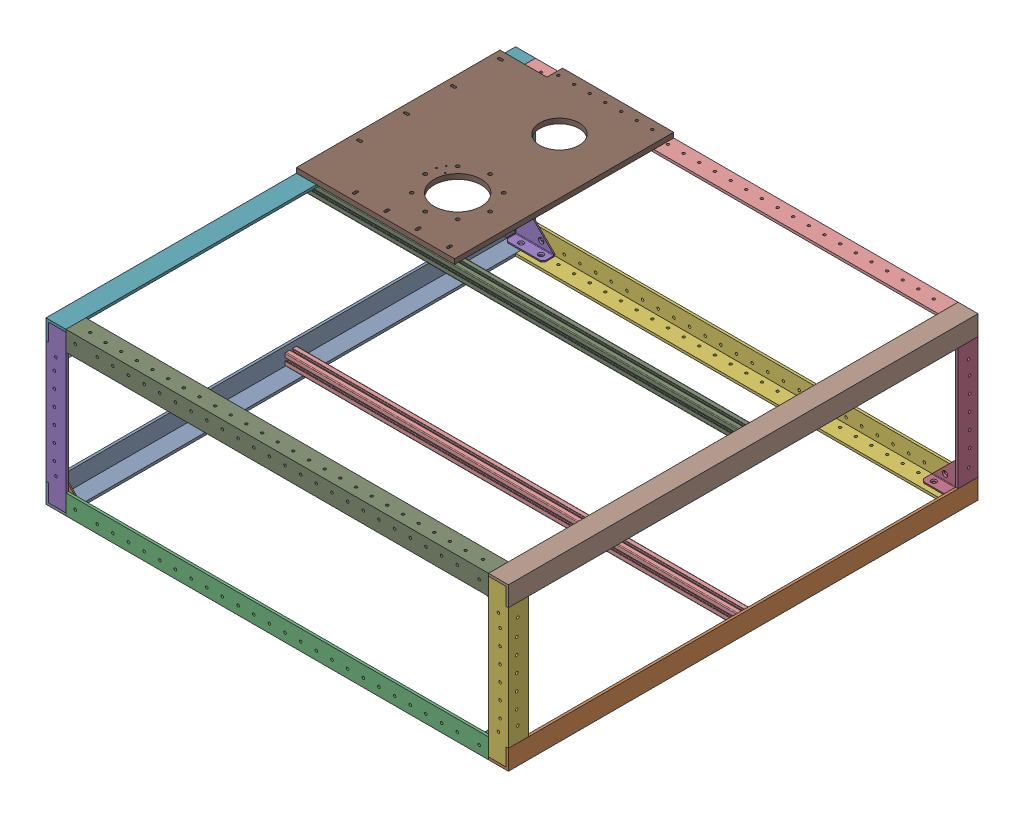
SolidWorks assembly URC Frame Assembly 2025, configuration Default. Lengths in mm.
Overall size (590.8 212.69 600).
23 component instances, 6 part files, 91 mates.
Components (placement in the parent):
- 600mm L Angle 0.125 in-2: 600mm L Angle 0.125 in [8982K421] at (-25.1001 123.5857 -689.9173) size (25.4 25.4 600)
- 600mm L Angle 0.125 in-3: 600mm L Angle 0.125 in [8982K421] at (565.6999 123.5807 1148.4827) x (-1 0 0) z (0 0 -1) size (25.4 25.4 600)
- 200mm L Angle 0.125 in-1: 200mm L Angle 0.125 in [8982K421] at (-25.1001 -892.4443 -70.7173) x (0 0 1) z (0 1 0) size (25.4 25.4 200)
- 200mm L Angle 0.125 in-2: 200mm L Angle 0.125 in [8982K421] at (565.6999 1345.9557 -70.7173) x (0 0 1) z (0 -1 0) size (25.4 25.4 200)
- 200mm L Angle 0.125 in-3: 200mm L Angle 0.125 in [8982K421] at (-25.1001 1345.9607 529.2827) x (0 0 -1) z (0 -1 0) size (25.4 25.4 200)
- 200mm L Angle 0.125 in-4: 200mm L Angle 0.125 in [8982K421] at (565.6999 -892.4443 529.2827) x (0 0 -1) z (0 1 0) size (25.4 25.4 200)
- 600mm L Angle 0.125 in-5: 600mm L Angle 0.125 in [8982K421] at (-25.1001 329.9257 -689.9173) x (0 -1 0) z (0 0 1) size (25.4 25.4 600)
- 600mm L Angle 0.125 in-6: 600mm L Angle 0.125 in [8982K421] at (565.6999 329.9257 -689.9173) x (-1 0 0) z (0 0 1) size (25.4 25.4 600)
- 584 mm L Angle 0.125 in-5: 584 mm L Angle 0.125 in [8982K421] at (-678.9001 329.9257 529.2827) x (0 -1 0) z (1 0 0) size (25.4 25.4 540)
- 584 mm L Angle 0.125 in-6: 584 mm L Angle 0.125 in [8982K421] at (1219.4999 329.9257 -70.7173) x (0 -1 0) z (-1 0 0) size (25.4 25.4 540)
- 1088A31_Inside-Corner Reinforcing Bracket-1: 1088A31_Inside-Corner Reinforcing Bracket [1088A31] at (562.5249 326.7507 524.5837) x (-1 0 0) z (0 -1 0) size (50.93 15.88 50.93)
- 1088A31_Inside-Corner Reinforcing Bracket-2: 1088A31_Inside-Corner Reinforcing Bracket [1088A31] at (-21.9251 326.7507 524.5837) x (0 -1 0) z (1 0 0) size (50.93 15.88 50.93)
- 1088A31_Inside-Corner Reinforcing Bracket-3: 1088A31_Inside-Corner Reinforcing Bracket [1088A31] at (562.5249 126.7557 524.5837) x (0 1 0) z (-1 0 0) size (50.93 15.88 50.93)
- 1088A31_Inside-Corner Reinforcing Bracket-4: 1088A31_Inside-Corner Reinforcing Bracket [1088A31] at (-21.9251 126.7607 524.5837) x (1 0 0) z (0 1 0) size (50.93 15.88 50.93)
- 584 mm L Angle 0.125 in-7: 584 mm L Angle 0.125 in [8982K421] at (1219.4999 123.5807 529.2827) x (0 1 0) z (-1 0 0) size (25.4 25.4 540)
- 1088A31_Inside-Corner Reinforcing Bracket-5: 1088A31_Inside-Corner Reinforcing Bracket [1088A31] at (562.5249 126.7607 -66.0183) x (-1 0 0) z (0 1 0) size (50.93 15.88 50.93)
- 1088A31_Inside-Corner Reinforcing Bracket-6: 1088A31_Inside-Corner Reinforcing Bracket [1088A31] at (-21.9251 126.7607 -66.0183) x (0 1 0) z (1 0 0) size (50.93 15.88 50.93)
- 584 mm L Angle 0.125 in-9: 584 mm L Angle 0.125 in [8982K421] at (-678.9001 123.5857 -70.7173) x (0 1 0) z (1 0 0) size (25.4 25.4 540)
- 1088A31_Inside-Corner Reinforcing Bracket-7: 1088A31_Inside-Corner Reinforcing Bracket [1088A31] at (562.5249 326.7507 -66.0183) x (0 -1 0) z (-1 0 0) size (50.93 15.88 50.93)
- 1088A31_Inside-Corner Reinforcing Bracket-8: 1088A31_Inside-Corner Reinforcing Bracket [1088A31] at (-21.9251 326.7507 -66.0183) x (1 0 0) z (0 -1 0) size (50.93 15.88 50.93)
- T Slot Extrusion-1: T Slot Extrusion [Default] at (92.5749 319.2507 199.2827) x (0 0 1) z (-1 0 0) size (15 15 584.45)
- T Slot Extrusion-2: T Slot Extrusion [Default] at (92.5749 134.2607 219.2827) x (0 0 1) z (-1 0 0) size (15 15 584.45)
- 2025 Arm Plate-1: 2025 Arm Plate [Default] at (105.8999 329.9257 69.2827) size (202 6.35 280)
Mates (geometry in assembly coordinates):
- Coincident10: coincident anti-aligned: plane of 600mm L Angle 0.125 in-2 through (0.2999 123.5857 529.2827) normal (1 0 0); plane of 584 mm L Angle 0.125 in-3 through (0.2999 123.5857 -70.7173) normal (-1 0 0)
- Coincident11: coincident aligned: plane of 600mm L Angle 0.125 in-2 through (0.2999 126.7607 529.2827) normal (0 1 0); plane of 584 mm L Angle 0.125 in-3 through (0.2999 126.7607 -45.3173) normal (0 1 0)
- Coincident12: coincident aligned: plane of 600mm L Angle 0.125 in-2 through (34.8999 148.9857 -70.7173) normal (0 0 -1); plane of 584 mm L Angle 0.125 in-3 through (0.2999 148.9857 -70.7173) normal (0 0 -1)
- Coincident16: coincident aligned: plane of 584 mm L Angle 0.125 in-3 through (0.2999 126.7607 -45.3173) normal (0 1 0); plane of 600mm L Angle 0.125 in-3 through (540.2999 126.7557 -70.7173) normal (0 1 0)
- Coincident17: coincident anti-aligned: plane of 584 mm L Angle 0.125 in-3 through (540.2999 148.9857 -10.7173) normal (1 0 0); plane of 600mm L Angle 0.125 in-3 through (540.2999 123.5807 -70.7173) normal (-1 0 0)
- Coincident18: coincident aligned: plane of 584 mm L Angle 0.125 in-3 through (0.2999 148.9857 -70.7173) normal (0 0 -1); plane of 600mm L Angle 0.125 in-3 through (565.6999 123.5807 -70.7173) normal (0 0 -1)
- Coincident19: coincident anti-aligned: plane of 600mm L Angle 0.125 in-3 through (540.2999 123.5807 -70.7173) normal (-1 0 0); plane of 584 mm L Angle 0.125 in-4 through (540.2999 123.5857 529.2827) normal (1 0 0)
- Coincident20: coincident aligned: plane of 600mm L Angle 0.125 in-3 through (540.2999 126.7557 -70.7173) normal (0 1 0); plane of 584 mm L Angle 0.125 in-4 through (540.2999 126.7607 503.8827) normal (0 1 0)
- Coincident21: coincident aligned: plane of 600mm L Angle 0.125 in-2 through (-25.1001 123.5857 529.2827) normal (0 0 1); plane of 584 mm L Angle 0.125 in-4 through (540.2999 148.9857 529.2827) normal (0 0 1)
- Coincident22: coincident aligned: plane of 600mm L Angle 0.125 in-2 through (-25.1001 148.9857 529.2827) normal (-1 0 0); plane of 200mm L Angle 0.125 in-1 through (-25.1001 326.7557 -70.7173) normal (-1 0 0)
- Coincident23: coincident aligned: plane of 584 mm L Angle 0.125 in-3 through (0.2999 148.9857 -70.7173) normal (0 0 -1); plane of 200mm L Angle 0.125 in-1 through (0.2999 326.7557 -70.7173) normal (0 0 -1)
- Coincident24: coincident anti-aligned: plane of 600mm L Angle 0.125 in-2 through (-21.9251 148.9857 529.2827) normal (0 1 0); plane of 200mm L Angle 0.125 in-1 through (11.8289 148.9857 -45.3173) normal (0 -1 0)
- Coincident25: coincident anti-aligned: plane of 600mm L Angle 0.125 in-3 through (540.2999 126.7557 -70.7173) normal (0 1 0); plane of 200mm L Angle 0.125 in-2 through (565.6999 126.7557 -70.7173) normal (0 -1 0)
- Coincident26: coincident aligned: plane of 584 mm L Angle 0.125 in-3 through (0.2999 148.9857 -70.7173) normal (0 0 -1); plane of 200mm L Angle 0.125 in-2 through (540.2999 126.7557 -70.7173) normal (0 0 -1)
- Coincident27: coincident aligned: plane of 600mm L Angle 0.125 in-3 through (565.6999 148.9807 -70.7173) normal (1 0 0); plane of 200mm L Angle 0.125 in-2 through (565.6999 126.7557 -70.7173) normal (1 0 0)
- Coincident28: coincident anti-aligned: plane of 600mm L Angle 0.125 in-2 through (0.2999 126.7607 529.2827) normal (0 1 0); plane of 200mm L Angle 0.125 in-3 through (-25.1001 126.7607 529.2827) normal (0 -1 0)
- Coincident29: coincident aligned: plane of 584 mm L Angle 0.125 in-4 through (540.2999 148.9857 529.2827) normal (0 0 1); plane of 200mm L Angle 0.125 in-3 through (0.2999 126.7607 529.2827) normal (0 0 1)
- Coincident30: coincident aligned: plane of 600mm L Angle 0.125 in-2 through (-25.1001 148.9857 529.2827) normal (-1 0 0); plane of 200mm L Angle 0.125 in-3 through (-25.1001 126.7607 529.2827) normal (-1 0 0)
- Coincident33: coincident anti-aligned: plane of 600mm L Angle 0.125 in-3 through (540.2999 126.7557 -70.7173) normal (0 1 0); plane of 200mm L Angle 0.125 in-4 through (540.2999 126.7557 469.2827) normal (0 -1 0)
- Coincident34: coincident aligned: plane of 584 mm L Angle 0.125 in-4 through (540.2999 148.9857 529.2827) normal (0 0 1); plane of 200mm L Angle 0.125 in-4 through (540.2999 326.7557 529.2827) normal (0 0 1)
- Coincident35: coincident aligned: plane of 600mm L Angle 0.125 in-3 through (565.6999 148.9807 -70.7173) normal (1 0 0); plane of 200mm L Angle 0.125 in-4 through (565.6999 326.7557 529.2827) normal (1 0 0)
- Coincident36: coincident aligned: plane of 200mm L Angle 0.125 in-3 through (-25.1001 126.7607 529.2827) normal (-1 0 0); plane of 600mm L Angle 0.125 in-4 through (-25.1001 129.9357 250.1294) normal (-1 0 0)
- Coincident37: coincident anti-aligned: plane of 600mm L Angle 0.125 in-2 through (0.2999 126.7607 529.2827) normal (0 1 0); plane of 600mm L Angle 0.125 in-4 through (-21.9251 126.7607 250.1294) normal (0 -1 0)
- Coincident39: coincident anti-aligned: plane of 200mm L Angle 0.125 in-1 through (11.8289 304.5257 -45.3173) normal (0 1 0); plane of 600mm L Angle 0.125 in-5 through (-25.1001 304.5257 529.2827) normal (0 -1 0)
- Coincident40: coincident aligned: plane of 200mm L Angle 0.125 in-1 through (0.2999 326.7557 -70.7173) normal (0 0 -1); plane of 600mm L Angle 0.125 in-5 through (0.2999 269.9257 -70.7173) normal (0 0 -1)
- Coincident41: coincident aligned: plane of 200mm L Angle 0.125 in-1 through (-25.1001 326.7557 -70.7173) normal (-1 0 0); plane of 600mm L Angle 0.125 in-5 through (-25.1001 329.9257 529.2827) normal (-1 0 0)
- Coincident42: coincident aligned: plane of 200mm L Angle 0.125 in-4 through (565.6999 326.7557 529.2827) normal (1 0 0); plane of 600mm L Angle 0.125 in-6 through (565.6999 304.5257 529.2827) normal (1 0 0)
- Coincident43: coincident anti-aligned: plane of 200mm L Angle 0.125 in-4 through (528.7709 304.5257 503.8827) normal (0 1 0); plane of 600mm L Angle 0.125 in-6 through (562.5249 304.5257 529.2827) normal (0 -1 0)
- Coincident44: coincident aligned: plane of 200mm L Angle 0.125 in-4 through (540.2999 326.7557 529.2827) normal (0 0 1); plane of 600mm L Angle 0.125 in-6 through (565.6999 329.9257 529.2827) normal (0 0 1)
- Coincident45: coincident anti-aligned: plane of 600mm L Angle 0.125 in-6 through (540.2999 329.9257 529.2827) normal (-1 0 0); plane of 584 mm L Angle 0.125 in-5 through (540.2999 329.9257 529.2827) normal (1 0 0)
- Coincident46: coincident aligned: plane of 200mm L Angle 0.125 in-4 through (540.2999 326.7557 529.2827) normal (0 0 1); plane of 584 mm L Angle 0.125 in-5 through (540.2999 329.9257 529.2827) normal (0 0 1)
- Coincident47: coincident aligned: plane of 600mm L Angle 0.125 in-6 through (565.6999 329.9257 529.2827) normal (0 1 0); plane of 584 mm L Angle 0.125 in-5 through (540.2999 329.9257 503.8827) normal (0 1 0)
- Coincident48: coincident aligned: plane of 200mm L Angle 0.125 in-2 through (540.2999 126.7557 -70.7173) normal (0 0 -1); plane of 584 mm L Angle 0.125 in-6 through (0.2999 329.9257 -70.7173) normal (0 0 -1)
- Coincident49: coincident aligned: plane of 600mm L Angle 0.125 in-6 through (565.6999 329.9257 529.2827) normal (0 1 0); plane of 584 mm L Angle 0.125 in-6 through (0.2999 329.9257 -45.3173) normal (0 1 0)
- Coincident50: coincident anti-aligned: plane of 600mm L Angle 0.125 in-5 through (0.2999 326.7507 529.2827) normal (1 0 0); plane of 584 mm L Angle 0.125 in-6 through (0.2999 329.9257 -70.7173) normal (-1 0 0)
- Concentric1: concentric aligned: circle of 600mm L Angle 0.125 in-6; circle of 1088A31_Inside-Corner Reinforcing Bracket-1
- Parallel2: parallel aligned: plane of 200mm L Angle 0.125 in-4 through (565.6999 326.7557 503.8827) normal (0 0 -1); plane of 1088A31_Inside-Corner Reinforcing Bracket-1 through (562.5249 325.2267 510.2327) normal (0 0 -1)
- Coincident52: coincident anti-aligned: plane of 200mm L Angle 0.125 in-4 through (562.5249 326.7557 503.8827) normal (-1 0 0); plane of 1088A31_Inside-Corner Reinforcing Bracket-1 through (562.5249 275.9507 524.5837) normal (1 0 0)
- Concentric2: concentric anti-aligned: circle of 600mm L Angle 0.125 in-5; circle of 1088A31_Inside-Corner Reinforcing Bracket-2
- Coincident53: coincident anti-aligned: plane of 200mm L Angle 0.125 in-3 through (-21.9251 126.7607 526.1077) normal (0 0 -1); plane of 1088A31_Inside-Corner Reinforcing Bracket-2 through (-20.4011 325.2267 526.1077) normal (0 0 1)
- Coincident54: coincident anti-aligned: plane of 600mm L Angle 0.125 in-5 through (-21.9251 304.5257 529.2827) normal (1 0 0); plane of 1088A31_Inside-Corner Reinforcing Bracket-2 through (-21.9251 275.9507 510.2327) normal (-1 0 0)
- Coincident55: coincident anti-aligned: plane of 200mm L Angle 0.125 in-4 through (562.5249 326.7557 503.8827) normal (-1 0 0); plane of 1088A31_Inside-Corner Reinforcing Bracket-3 through (562.5249 177.5557 510.2327) normal (1 0 0)
- Coincident56: coincident anti-aligned: plane of 200mm L Angle 0.125 in-4 through (562.5249 326.7557 526.1077) normal (0 0 -1); plane of 1088A31_Inside-Corner Reinforcing Bracket-3 through (561.0009 128.2797 526.1077) normal (0 0 1)
- Coincident57: coincident anti-aligned: plane of 600mm L Angle 0.125 in-3 through (540.2999 126.7557 -70.7173) normal (0 1 0); plane of 1088A31_Inside-Corner Reinforcing Bracket-3 through (511.7249 126.7557 524.5837) normal (0 -1 0)
- Coincident58: coincident anti-aligned: plane of 600mm L Angle 0.125 in-2 through (0.2999 126.7607 529.2827) normal (0 1 0); plane of 1088A31_Inside-Corner Reinforcing Bracket-4 through (28.8749 126.7607 510.2327) normal (0 -1 0)
- Coincident59: coincident anti-aligned: plane of 200mm L Angle 0.125 in-3 through (-21.9251 126.7607 526.1077) normal (0 0 -1); plane of 1088A31_Inside-Corner Reinforcing Bracket-4 through (-20.4011 128.2847 526.1077) normal (0 0 1)
- Coincident60: coincident anti-aligned: plane of 200mm L Angle 0.125 in-3 through (-21.9251 126.7607 503.8827) normal (1 0 0); plane of 1088A31_Inside-Corner Reinforcing Bracket-4 through (-21.9251 177.5607 524.5837) normal (-1 0 0)
- Coincident61: coincident aligned: plane of 600mm L Angle 0.125 in-3 through (565.6999 123.5807 -70.7173) normal (0 -1 0); plane of 584 mm L Angle 0.125 in-7 through (0.2999 123.5807 503.8827) normal (0 -1 0)
- Coincident62: coincident aligned: plane of 200mm L Angle 0.125 in-4 through (540.2999 326.7557 529.2827) normal (0 0 1); plane of 584 mm L Angle 0.125 in-7 through (0.2999 123.5807 529.2827) normal (0 0 1)
- Coincident64: coincident anti-aligned: plane of 600mm L Angle 0.125 in-3 through (540.2999 123.5807 -70.7173) normal (-1 0 0); plane of 584 mm L Angle 0.125 in-7 through (540.2999 183.5807 503.8827) normal (1 0 0)
- Coincident65: coincident aligned: plane of 200mm L Angle 0.125 in-2 through (540.2999 126.7557 -70.7173) normal (0 0 -1); plane of 600mm L Angle 0.125 in-6 through (505.6999 304.5257 -70.7173) normal (0 0 -1)
- Coincident66: coincident: plane of 584 mm L Angle 0.125 in-3 through (0.2999 126.7607 -45.3173) normal (0 1 0); plane of 1088A31_Inside-Corner Reinforcing Bracket-5 through (511.7249 126.7607 -51.6673) normal (0 -1 0)
- Coincident67: coincident: plane of 584 mm L Angle 0.125 in-3 through (0.2999 126.7607 -67.5423) normal (0 0 1); plane of 1088A31_Inside-Corner Reinforcing Bracket-5 through (561.0009 128.2847 -67.5423) normal (0 0 -1)
- Coincident68: coincident anti-aligned: plane of 200mm L Angle 0.125 in-2 through (562.5249 126.7557 -45.3173) normal (-1 0 0); plane of 1088A31_Inside-Corner Reinforcing Bracket-5 through (562.5249 177.5607 -66.0183) normal (1 0 0)
- Parallel3: parallel anti-aligned: plane of 584 mm L Angle 0.125 in-7 through (0.2999 126.7557 503.8827) normal (0 0 -1); plane of 584 mm L Angle 0.125 in-8 through (0.2999 123.5857 -45.3173) normal (0 0 1)
- Coincident70: coincident aligned: plane of 600mm L Angle 0.125 in-2 through (-25.1001 123.5857 529.2827) normal (0 -1 0); plane of 584 mm L Angle 0.125 in-8 through (0.2999 123.5857 -70.7173) normal (0 -1 0)
- Coincident71: coincident aligned: plane of 200mm L Angle 0.125 in-1 through (0.2999 326.7557 -70.7173) normal (0 0 -1); plane of 584 mm L Angle 0.125 in-8 through (0.2999 148.9857 -70.7173) normal (0 0 -1)
- Coincident72: coincident anti-aligned: plane of 200mm L Angle 0.125 in-1 through (0.2999 326.7557 -67.5423) normal (1 0 0); plane of 584 mm L Angle 0.125 in-8 through (0.2999 123.5857 -70.7173) normal (-1 0 0)
- Coincident73: coincident anti-aligned: plane of 1088A31_Inside-Corner Reinforcing Bracket-5 through (561.0009 128.2847 -67.5423) normal (0 0 -1); plane of 584 mm L Angle 0.125 in-8 through (0.2999 126.7607 -67.5423) normal (0 0 1)
- Coincident74: coincident aligned: plane of 200mm L Angle 0.125 in-2 through (540.2999 126.7557 -70.7173) normal (0 0 -1); plane of 584 mm L Angle 0.125 in-8 through (0.2999 148.9857 -70.7173) normal (0 0 -1)
- Coincident75: coincident aligned: plane of 600mm L Angle 0.125 in-3 through (565.6999 123.5807 -70.7173) normal (0 0 -1); plane of 584 mm L Angle 0.125 in-8 through (0.2999 148.9857 -70.7173) normal (0 0 -1)
- Coincident76: coincident aligned: plane of 600mm L Angle 0.125 in-2 through (34.8999 148.9857 -70.7173) normal (0 0 -1); plane of 584 mm L Angle 0.125 in-8 through (0.2999 148.9857 -70.7173) normal (0 0 -1)
- Coincident77: coincident aligned: plane of 600mm L Angle 0.125 in-5 through (0.2999 329.9257 529.2827) normal (0 1 0); plane of 584 mm L Angle 0.125 in-6 through (0.2999 329.9257 -45.3173) normal (0 1 0)
- Coincident78: coincident anti-aligned: plane of 600mm L Angle 0.125 in-5 through (0.2999 326.7507 529.2827) normal (1 0 0); plane of 584 mm L Angle 0.125 in-5 through (0.2999 269.9257 503.8827) normal (-1 0 0)
- Coincident79: coincident anti-aligned: plane of 200mm L Angle 0.125 in-1 through (-21.9251 326.7557 -67.5423) normal (0 0 1); plane of 1088A31_Inside-Corner Reinforcing Bracket-6 through (-20.4011 128.2847 -67.5423) normal (0 0 -1)
- Coincident80: coincident anti-aligned: plane of 200mm L Angle 0.125 in-1 through (-21.9251 326.7557 -45.3173) normal (1 0 0); plane of 1088A31_Inside-Corner Reinforcing Bracket-6 through (-21.9251 177.5607 -51.6673) normal (-1 0 0)
- Coincident81: coincident anti-aligned: plane of 584 mm L Angle 0.125 in-8 through (0.2999 126.7607 -45.3173) normal (0 1 0); plane of 1088A31_Inside-Corner Reinforcing Bracket-6 through (28.8749 126.7607 -66.0183) normal (0 -1 0)
- Coincident82: coincident aligned: plane of 600mm L Angle 0.125 in-2 through (0.2999 126.7607 529.2827) normal (0 1 0); plane of 584 mm L Angle 0.125 in-9 through (540.2999 126.7607 -67.5423) normal (0 1 0)
- Coincident83: coincident anti-aligned: plane of 1088A31_Inside-Corner Reinforcing Bracket-6 through (-20.4011 128.2847 -67.5423) normal (0 0 -1); plane of 584 mm L Angle 0.125 in-9 through (540.2999 148.9857 -67.5423) normal (0 0 1)
- Coincident84: coincident anti-aligned: plane of 600mm L Angle 0.125 in-3 through (540.2999 123.5807 -70.7173) normal (-1 0 0); plane of 584 mm L Angle 0.125 in-9 through (540.2999 123.5857 -70.7173) normal (1 0 0)
- Coincident85: coincident anti-aligned: plane of 1088A31_Inside-Corner Reinforcing Bracket-5 through (511.7249 126.7607 -51.6673) normal (0 -1 0); plane of 584 mm L Angle 0.125 in-9 through (540.2999 126.7607 -67.5423) normal (0 1 0)
- Coincident86: coincident anti-aligned: plane of 1088A31_Inside-Corner Reinforcing Bracket-5 through (561.0009 128.2847 -67.5423) normal (0 0 -1); plane of 584 mm L Angle 0.125 in-9 through (540.2999 148.9857 -67.5423) normal (0 0 1)
- Coincident87: coincident anti-aligned: plane of 200mm L Angle 0.125 in-2 through (562.5249 126.7557 -67.5423) normal (0 0 1); plane of 1088A31_Inside-Corner Reinforcing Bracket-5 through (561.0009 128.2847 -67.5423) normal (0 0 -1)
- Coincident88: coincident aligned: plane of 600mm L Angle 0.125 in-3 through (565.6999 123.5807 -70.7173) normal (0 0 -1); plane of 200mm L Angle 0.125 in-2 through (540.2999 126.7557 -70.7173) normal (0 0 -1)
- Coincident89: coincident aligned: plane of 600mm L Angle 0.125 in-2 through (-25.1001 123.5857 529.2827) normal (0 0 1); plane of 200mm L Angle 0.125 in-3 through (0.2999 126.7607 529.2827) normal (0 0 1)
- Coincident90: coincident anti-aligned: plane of 584 mm L Angle 0.125 in-6 through (0.2999 326.7507 -67.5423) normal (0 -1 0); plane of 1088A31_Inside-Corner Reinforcing Bracket-7 through (511.7249 326.7507 -66.0183) normal (0 1 0)
- Coincident91: coincident anti-aligned: plane of 584 mm L Angle 0.125 in-6 through (0.2999 304.5257 -67.5423) normal (0 0 1); plane of 1088A31_Inside-Corner Reinforcing Bracket-7 through (561.0009 325.2267 -67.5423) normal (0 0 -1)
- Coincident92: coincident anti-aligned: plane of 600mm L Angle 0.125 in-6 through (562.5249 326.7507 529.2827) normal (-1 0 0); plane of 1088A31_Inside-Corner Reinforcing Bracket-7 through (562.5249 275.9507 -51.6673) normal (1 0 0)
- Coincident93: coincident anti-aligned: plane of 200mm L Angle 0.125 in-1 through (-21.9251 326.7557 -67.5423) normal (0 0 1); plane of 1088A31_Inside-Corner Reinforcing Bracket-8 through (-20.4011 325.2267 -67.5423) normal (0 0 -1)
- Coincident94: coincident anti-aligned: plane of 200mm L Angle 0.125 in-1 through (-21.9251 326.7557 -45.3173) normal (1 0 0); plane of 1088A31_Inside-Corner Reinforcing Bracket-8 through (-21.9251 275.9507 -66.0183) normal (-1 0 0)
- Coincident95: coincident anti-aligned: plane of 584 mm L Angle 0.125 in-6 through (0.2999 326.7507 -67.5423) normal (0 -1 0); plane of 1088A31_Inside-Corner Reinforcing Bracket-8 through (28.8749 326.7507 -51.6673) normal (0 1 0)
- Coincident96: coincident anti-aligned: plane of 600mm L Angle 0.125 in-2 through (0.2999 126.7607 529.2827) normal (0 1 0); plane of 1088A31_Inside-Corner Reinforcing Bracket-6 through (28.8749 126.7607 -66.0183) normal (0 -1 0)
- Coincident97: coincident anti-aligned: plane of 600mm L Angle 0.125 in-5 through (-21.9251 304.5257 529.2827) normal (1 0 0); plane of T Slot Extrusion-1 through (-21.9251 325.7507 192.7827) normal (-1 0 0)
- Parallel4: parallel aligned: plane of 600mm L Angle 0.125 in-5 through (0.2999 329.9257 529.2827) normal (0 1 0); plane of T Slot Extrusion-1 through (562.5249 326.7507 197.2827) normal (0 1 0)
- Coincident99: coincident anti-aligned: plane of 600mm L Angle 0.125 in-2 through (-21.9251 126.7607 529.2827) normal (1 0 0); plane of T Slot Extrusion-2 through (-21.9251 140.7607 212.7827) normal (-1 0 0)
- Parallel5: parallel aligned: plane of 600mm L Angle 0.125 in-2 through (-21.9251 148.9857 529.2827) normal (0 1 0); plane of T Slot Extrusion-2 through (562.5249 141.7607 225.7827) normal (0 1 0)
- Concentric8: concentric anti-aligned: circle of 600mm L Angle 0.125 in-2; circle of T Slot Extrusion-2
- Concentric9: concentric aligned: circle of 584 mm L Angle 0.125 in-6; circle of 2025 Arm Plate-1
- Concentric10: concentric aligned: circle of 584 mm L Angle 0.125 in-6; circle of 2025 Arm Plate-1
- Coincident102: coincident anti-aligned: plane of 600mm L Angle 0.125 in-5 through (0.2999 329.9257 529.2827) normal (0 1 0); plane of 2025 Arm Plate-1 through (105.8999 329.9257 69.2827) normal (0 -1 0)
- Concentric11: concentric aligned: circle of 600mm L Angle 0.125 in-6; circle of T Slot Extrusion-1
